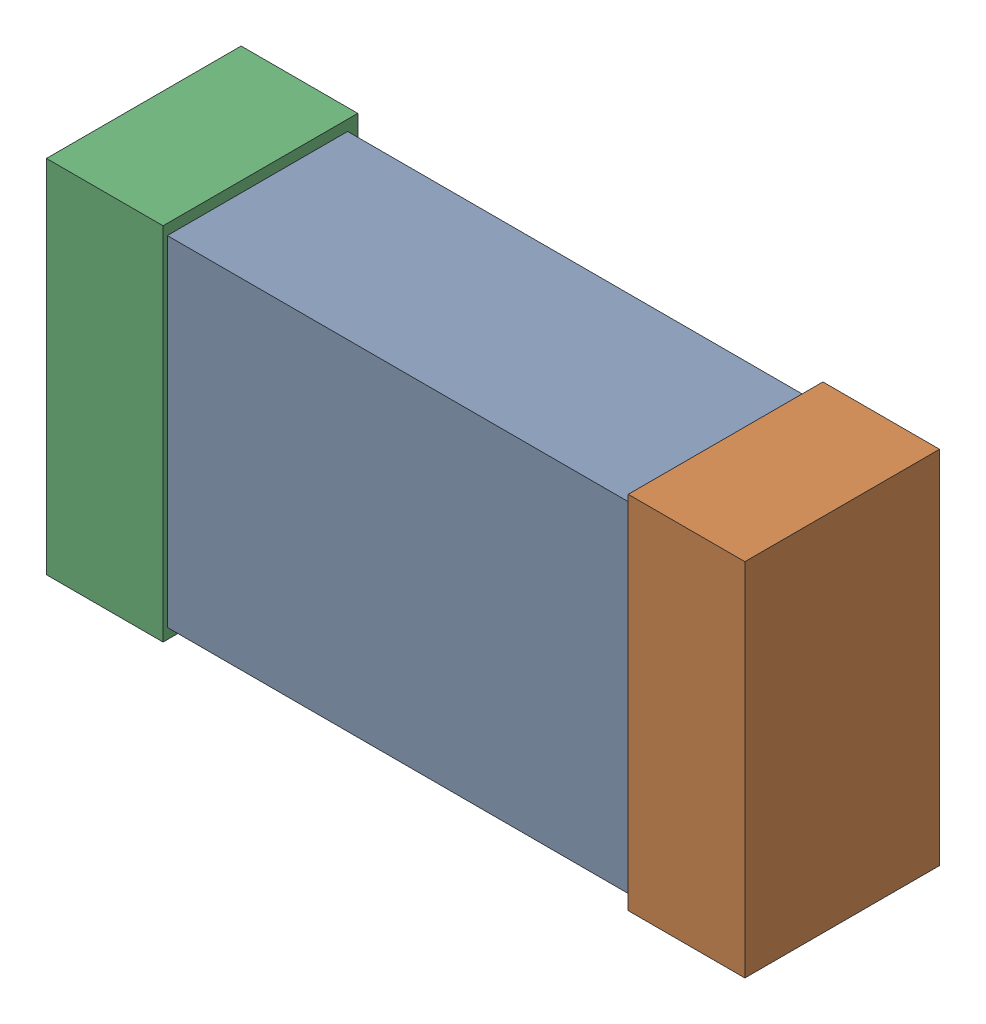
SolidWorks assembly C19, configuration Default. Lengths in mm.
Overall size (1.65 0.85 0.46).
6 component instances, 2 part files, 0 mates.
Components (placement in the parent):
- 432120720_12-1: 432120720_12 [Default] at (31.0953 10.4865 0.025) size (1.5 0.8 0.42)
  - Extruded (12)-1: Extruded (12) [Default] at origin size (1.5 0.8 0.42)
- 432120464_24-1: 432120464_24 [Default] at (31.7811 10.4865 0.001) size (0.28 0.85 0.46)
  - Extruded (11)-1: Extruded (11) [Default] at origin size (0.28 0.85 0.46)
- 432120464_25-1: 432120464_25 [Default] at (30.4095 10.4865 0.001) size (0.28 0.85 0.46)
  - Extruded (11)-1: Extruded (11) [Default] at origin size (0.28 0.85 0.46)
